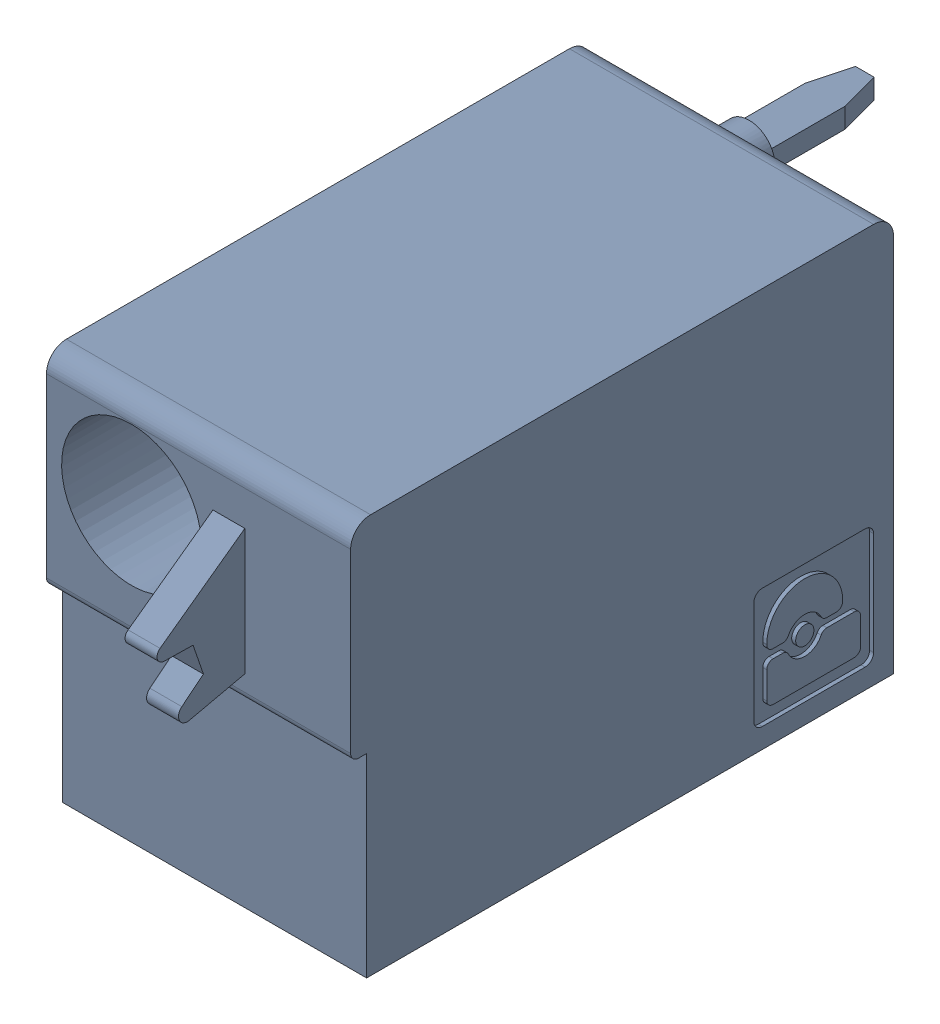
SolidWorks assembly J9, configuration Default. Lengths in mm.
Overall size (7.62 10 19.2).
2 component instances, 1 part files, 0 mates.
Components (placement in the parent):
- 1790487-1: 1790487 [Default] at (8.025 -5.67 -10.6) x (0 1 0) z (1 0 0) size (10 19.2 7.62)
  - ffkdsa1-v2-7.62-1: ffkdsa1-v2-7.62 [Default] at (-15.6914 -27.508 9.12) x (0 -1 0) z (0 0 1) size (19.2 10 7.62)
